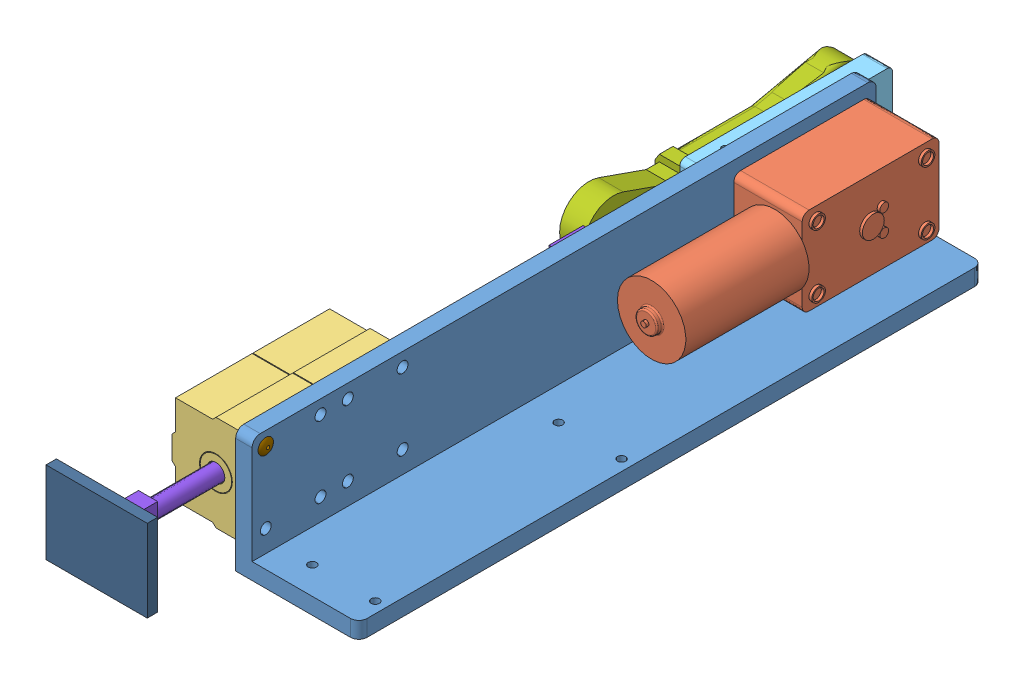
SolidWorks assembly DC_assembly, configuration Default. Lengths in mm.
Overall size (72.5 45 286.13).
12 component instances, 11 part files, 7 mates.
Components (placement in the parent):
- Base_part-1: Base_part [Default] at origin size (45 45 228)
- DC_motor-1: DC_motor [Default] at origin size (27.5 32 98)
- Rod way-1: Rod way [Default] at origin size (25 35 56.3)
- Brown_small_rod-1: Brown_small_rod [Default] at (76.9692 0 0) x (0 0 1) z (-1 0 0) size (7.5 7.5 18)
- Back_rotat_part-1: Back_rotat_part [Default] at origin size (9 23.97 68.75)
- second_rod-1: second_rod [Default] at origin size (23 9.99 10.22)
- mid_rotat_part-1: mid_rotat_part [Default] at origin size (11.98 22.02 103.99)
- second_rod-2: second_rod [Default] at (0 0.0459 82.2557) size (23 9.99 10.22)
- Last_translation-2: Last_translation [Default] at (56.198 8.7261 100.9813) x (-0.91495 -0.403568 0) z (-0.403568 0.91495 0) size (12.55 197 16.77)
- screws-1: screws [Default] at origin size (10.88 5.61 5.61)
- soft pad-1: soft pad [Default] at origin size (37 30 13.81)
- Bolt-1: Bolt [Default] at origin size (12 7.25 6.84)
Mates (geometry in assembly coordinates):
- InPlace1: in place: plane of ? through (76.9692 -12.2 228) normal (-1 0 0); plane of Brown_small_rod-1 through (76.9692 0 0) normal (-1 0 0); moOrthogonalPlaneRef_w of ? through (76.9692 -12.2 228) normal (-1 0 0); plane of Brown_small_rod-1 through (76.9692 0 0) normal (0 1 0); plane of ? through (76.9692 -12.2 228) normal (-1 0 0); plane of Brown_small_rod-1 through (76.9692 0 0) normal (0 0 1); plane of ? through (76.9692 -12.2 228) normal (-1 0 0); unknown of Brown_small_rod-1
- Coincident1: coincident: plane of Base_part-1; plane of Brown_small_rod-1
- Coincident2: coincident: moOrthogonalPlaneRef_w of Base_part-1 through (76.9692 0 0) normal (0 1 0); plane of Brown_small_rod-1 through (76.9692 0 0) normal (0 1 0)
- Coincident3: coincident: moOrthogonalPlaneRef_w of Base_part-1 through (76.9692 0 0) normal (0 0 -1); plane of Brown_small_rod-1 through (76.9692 0 0) normal (0 0 1)
- Coincident1: coincident: plane of mid_rotat_part-1 through (54.9692 7.7856 -5.3448) normal (-1 0 0); plane of second_rod-2 through (54.9692 0.0459 82.2557) normal (1 0 0)
- Concentric1: concentric: cylinder of mid_rotat_part-1 through (63.9692 7.8315 76.9109) axis (-1 0 0) radius 4; cylinder of second_rod-2 through (74.9692 7.8315 76.9109) axis (-1 0 0) radius 3.75
- Concentric3: concentric: cylinder of Rod way-1 through (67.9692 7.55 144.2) axis (0 0 1) radius 6; cylinder of Last_translation-2 through (67.9692 7.55 250.9813) axis (0 0 -1) radius 3
